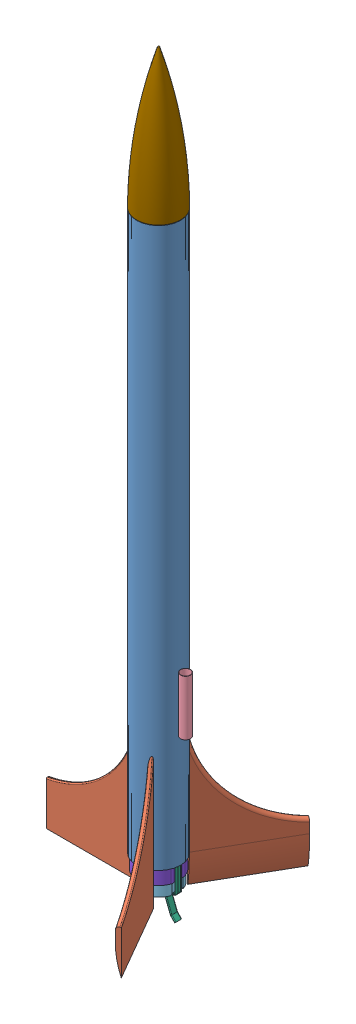
SolidWorks assembly rocket_assy_revised, configuration TDE331_Rocket120ms. Lengths in mm.
Overall size (77.56 339.65 88.6).
11 component instances, 9 part files, 25 mates.
Components (placement in the parent):
- body_tube-1: body_tube [Default] at origin
- balsa_fin-1: balsa_fin [Default] at (-9.9499 15 0) x (-1 0 0) z (0 0 -1)
- inside_ring-1: inside_ring [Default] at (0 62 0)
- launch_lug-1: launch_lug [Default] at (12.25 52 0)
- motor_casing-1: motor_casing [Default] at (0 -11.299 0)
- motor_clip-1: motor_clip [Default] at (8.7031 -22.65 0)
- motor_core-1: motor_core [Default] at (0 23.5714 0)
- motor_mount_tube-1: motor_mount_tube [Default] at (0 -6.35 0)
- nose_cone-1: nose_cone [Default] at (0 240 0)
- balsa_fin-2: balsa_fin [Default] at (4.9749 15 -8.6168) x (0.5 0 -0.866025) z (0.866025 0 0.5)
- balsa_fin-3: balsa_fin [Default] at (4.9749 15 8.6168) x (0.5 0 0.866025) z (-0.866025 0 0.5)
Mates (geometry in assembly coordinates):
- Concentric1: concentric aligned: cylinder of body_tube-1 through (0 253.5 0) axis (0 -1 0) radius 9.5; cylinder of inside_ring-1 through (0 72 0) axis (0 -1 0) radius 9.5
- Coincident1: coincident aligned: plane of inside_ring-1 through (0 62 0) normal (0 0 1); plane of assembly through (0 0 0) normal (0 0 1)
- Coincident2: coincident anti-aligned: plane of inside_ring-1 through (0 62 0) normal (0 -1 0); plane of assembly through (0 62 0) normal (0 1 0)
- Concentric2: concentric aligned: cylinder of body_tube-1 through (0 253.5 0) axis (0 -1 0) radius 10; cylinder of motor_mount_tube-1 through (0 56.65 0) axis (0 -1 0) radius 9.4
- Coincident3: coincident aligned: plane of motor_mount_tube-1 through (0 -6.35 0) normal (0 0 1); plane of assembly through (0 0 0) normal (0 0 1)
- Distance1: distance = 6.35 mm aligned: plane of body_tube-1 through (0 0 0) normal (0 -1 0); plane of motor_mount_tube-1 through (7 -6.35 0) normal (0 -1 0)
- Coincident5: coincident aligned: plane of motor_clip-1 through (8.7031 -22.65 0) normal (0 0 1); plane of assembly through (0 0 0) normal (0 0 1)
- Concentric3: concentric aligned: cylinder of motor_casing-1 through (0 58.701 0) axis (0 -1 0) radius 6.3; cylinder of motor_core-1 through (0 -15.5012 0) axis (0 -1 0) radius 6.3
- Tangent1: tangent: plane of motor_casing-1 through (7 -11.299 0) normal (0 -1 0); torus of motor_core-1
- Coincident7: coincident aligned: plane of motor_casing-1 through (0 -11.299 0) normal (0 0 1); plane of motor_core-1 through (0 23.5714 0) normal (0 0 1)
- Concentric4: concentric aligned: cylinder of motor_casing-1 through (0 58.701 0) axis (0 -1 0) radius 8.875; cylinder of body_tube-1 through (0 253.5 0) axis (0 -1 0) radius 9.5
- Distance4: distance = 0.001 mm anti-aligned: plane of motor_casing-1 through (7 -11.299 0) normal (0 -1 0); plane of motor_clip-1 through (3.0531 -11.3 1.5) normal (0 1 0)
- Tangent2: tangent anti-aligned: plane of inside_ring-1 through (0 62 0) normal (0 -1 0); cylinder of motor_clip-1 through (6.7031 59.35 1.5) axis (0 0 -1) radius 2.65
- Coincident10: coincident aligned: plane of body_tube-1 through (0 0 0) normal (0 0 1); plane of launch_lug-1 through (12.25 52 0) normal (0 0 1)
- Coincident11: coincident aligned: plane of launch_lug-1 through (12.25 52 0) normal (0 -1 0); plane of assembly through (0 52 0) normal (0 -1 0)
- Tangent3: tangent anti-aligned: cylinder of body_tube-1 through (0 253.5 0) axis (0 -1 0) radius 10; cylinder of launch_lug-1 through (12.25 77 0) axis (0 -1 0) radius 2.25
- Concentric6: concentric anti-aligned: cylinder of body_tube-1 through (0 253.5 0) axis (0 -1 0) radius 9.5; cylinder of nose_cone-1 through (0 320.2764 0) axis (0 1 0) radius 9.45
- Coincident12: coincident aligned: plane of body_tube-1 through (0 0 0) normal (0 0 1); plane of nose_cone-1 through (0 240 0) normal (0 0 1)
- Coincident13: coincident anti-aligned: plane of body_tube-1 through (0 253.5 0) normal (0 1 0); plane of nose_cone-1 through (-9.45 253.5 0) normal (0 -1 0)
- Concentric7: concentric anti-aligned: cylinder of body_tube-1 through (0 253.5 0) axis (0 -1 0) radius 10; cylinder of balsa_fin-1 through (0 -15 0) axis (0 1 0) radius 10
- Coincident14: coincident anti-aligned: plane of body_tube-1 through (0 0 0) normal (0 0 1); plane of balsa_fin-1 through (-9.9499 15 0) normal (0 0 -1)
- Coincident15: coincident: point of balsa_fin-1; plane of assembly
- Coincident16: coincident aligned: plane of motor_casing-1 through (0 -11.299 0) normal (0 0 1); plane of assembly through (0 0 0) normal (0 0 1)
- Distance3: distance = 8.7031 mm anti-aligned: plane of motor_clip-1 through (8.7031 -11.3 1.5) normal (-1 0 0); plane of assembly through (0 0 0) normal (1 0 0)
- Coincident18: coincident aligned: plane of motor_casing-1 through (0 -11.299 0) normal (0 0 1); plane of assembly through (0 0 0) normal (0 0 1)
